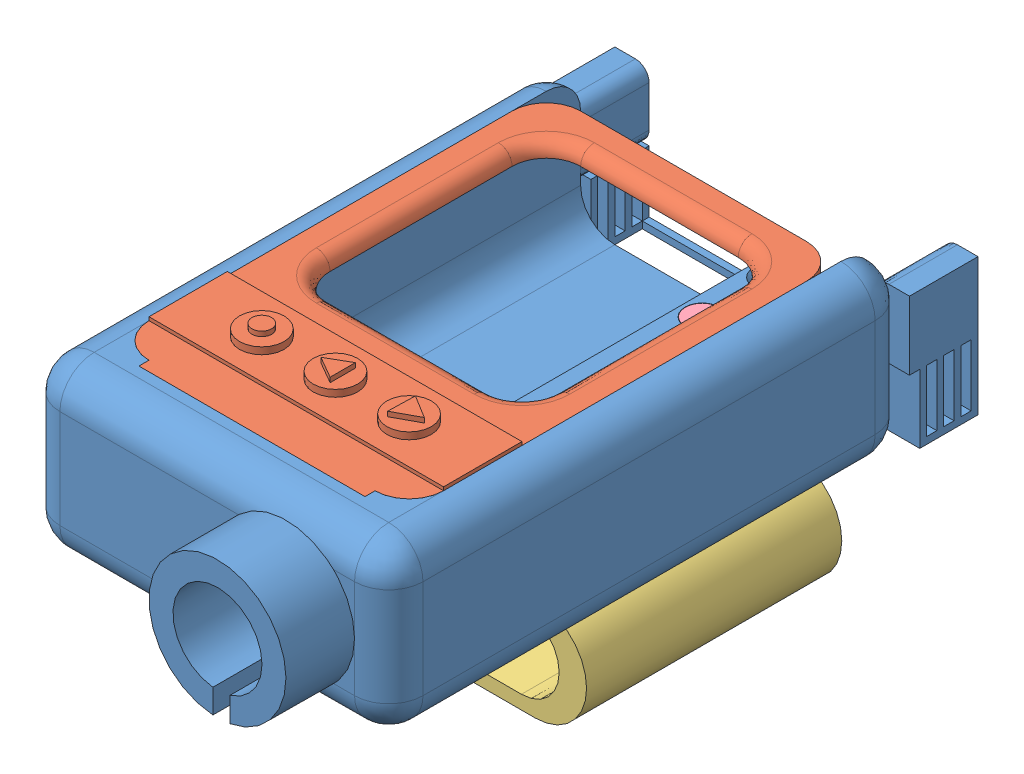
SolidWorks assembly Assem1, configuration Default. Lengths in mm.
Overall size (53 41.6 96).
5 component instances, 4 part files, 6 mates.
Components (placement in the parent):
- Part1-1: Part1 [Default] at (25.1873 29.9666 92.9835) size (53 24.51 96)
- Part5-1: Part5 [Default] at (25.1873 54.3666 91.4835) x (0 0 1) z (1 0 0) size (64.47 4.2 43)
- Part3-4: Part3 [Default] at (25.1946 22.4666 100.6207) x (1 0 0) z (0 1 0) size (50 60.79 15.09)
- Part4-12: Part4 [Default] at (27.2222 34.9666 109.4593) x (1 0 0) z (0 -1 0) size (4.89 4.89 8.12)
- Part4-13: Part4 [Default] at (27.2222 34.9666 62.2093) x (1 0 0) z (0 -1 0) size (4.89 4.89 8.12)
Mates (geometry in assembly coordinates):
- Parallel1: parallel anti-aligned: plane of Part1-1 through (25.1873 34.9666 92.9835) normal (0 1 0); plane of Part5-1 through (41.6873 52.3666 117.9835) normal (0 -1 0)
- Coincident7: coincident: point of Part1-1; unknown of Part5-1
- Coincident8: coincident: unknown of Part1-1; unknown of Part5-1
- Coincident59: coincident anti-aligned: plane of Part1-1 through (3.6873 29.9666 59.9835) normal (0 -1 0); plane of Part3-4 through (7.6946 29.9666 63.3707) normal (0 1 0)
- Concentric17: concentric anti-aligned: circle of Part1-1; circle of Part4-13
- Concentric18: concentric anti-aligned: circle of Part1-1; circle of Part4-12
